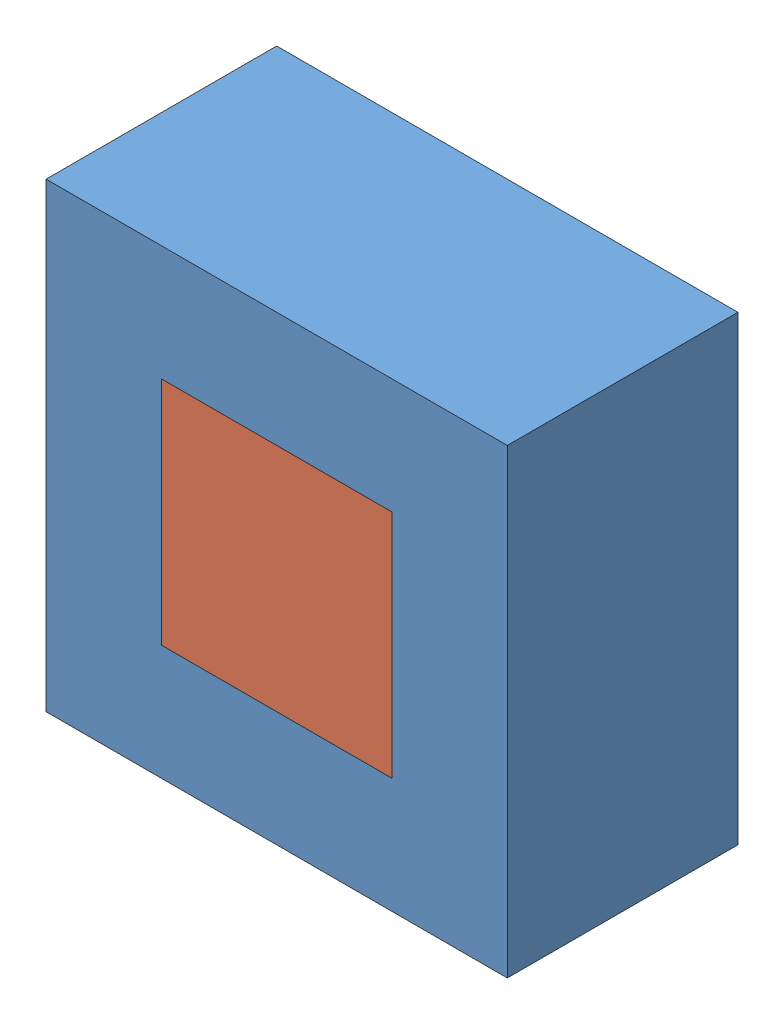
SolidWorks assembly Ass1, configuration Default. Lengths in mm.
Overall size (10 10 5).
2 component instances, 2 part files, 3 mates.
Components (placement in the parent):
- carre_troué-2: carre_troué [Default] at origin size (10 10 5)
- carre_vert-2: carre_vert [Default] at (0 0 3) size (5 5 2)
Mates (geometry in assembly coordinates):
- Coincident1: coincident: plane of carre_troué-2 through (0 0 3) normal (0 0 1); plane of carre_vert-1 through (0 0 3) normal (0 0 -1)
- Coincident2: coincident: plane of carre_troué-2 through (2.5 2.5 3) normal (-1 0 0); plane of carre_vert-1 through (2.5 2.5 5) normal (1 0 0)
- Coincident3: coincident anti-aligned: plane of carre_troué-2 through (-2.5 2.5 3) normal (0 -1 0); plane of carre_vert-1 through (-2.5 2.5 5) normal (0 1 0)
